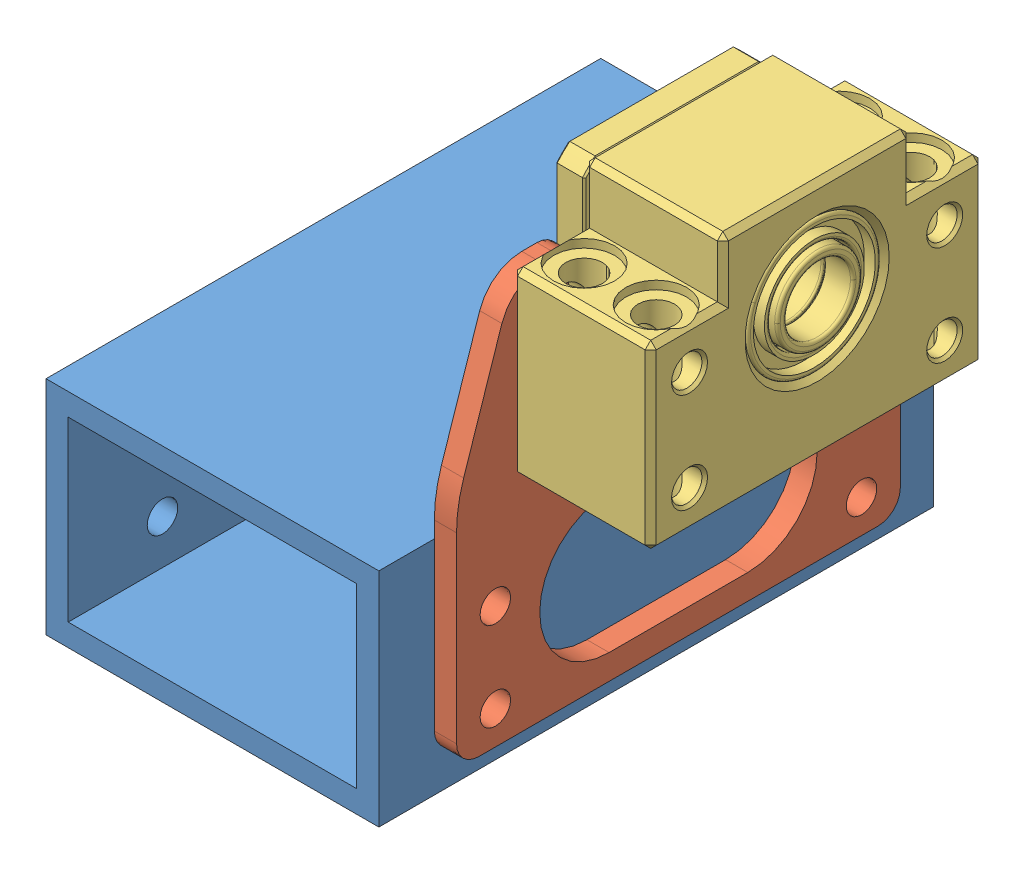
SolidWorks assembly Стойка опоры продольной оси, configuration По умолчанию. Lengths in mm.
Overall size (89.5 93.94 100).
3 component instances, 3 part files, 6 mates.
Components (placement in the parent):
- Труба стальная 60х40х4-1: Труба стальная 60х40х4 [100 с отверстиями] at (-41.8731 20.3219 21.5545) size (60 40 100)
- пластина подшипниковой опоры-1: пластина подшипниковой опоры [Увеличенная] at (-7.8731 54.3219 21.5545) x (0 0 1) z (-1 0 0) size (80 71 4)
- BK12-1: BK12 [Default] at (4.6269 47.3219 21.5545) x (0 0 1) z (-1 0 0) size (60 46.94 35.34)
Mates (geometry in assembly coordinates):
- Концентричный1: concentric anti-aligned: cylinder of Труба стальная 60х40х4-1 through (-71.8731 28.3219 54.5545) axis (-1 0 0) radius 2.75; cylinder of пластина подшипниковой опоры-1 through (-11.8731 28.3219 54.5545) axis (1 0 0) radius 2.75
- Концентричный2: concentric anti-aligned: cylinder of Труба стальная 60х40х4-1 through (-71.8731 12.3219 -11.4455) axis (-1 0 0) radius 2.75; cylinder of пластина подшипниковой опоры-1 through (-11.8731 12.3219 -11.4455) axis (1 0 0) radius 2.75
- Совпадение1: coincident anti-aligned: plane of Труба стальная 60х40х4-1 through (-11.8731 0.3219 -28.4455) normal (1 0 0); plane of пластина подшипниковой опоры-1 through (-11.8731 54.3219 21.5545) normal (-1 0 0)
- Концентричный4: concentric anti-aligned: cylinder of пластина подшипниковой опоры-1 through (-11.8731 72.3219 44.5545) axis (1 0 0) radius 2.75; cylinder of BK12-1 through (-3.6752 72.3219 44.5545) axis (-1 0 0) radius 2.75
- Концентричный5: concentric anti-aligned: cylinder of пластина подшипниковой опоры-1 through (-11.8731 54.3219 -1.4455) axis (1 0 0) radius 2.75; cylinder of BK12-1 through (-3.6752 54.3219 -1.4455) axis (-1 0 0) radius 2.75
- Совпадение2: coincident anti-aligned: plane of пластина подшипниковой опоры-1 through (-7.8731 54.3219 21.5545) normal (1 0 0); plane of BK12-1 through (-7.8731 48.3219 -7.4455) normal (-1 0 0)
